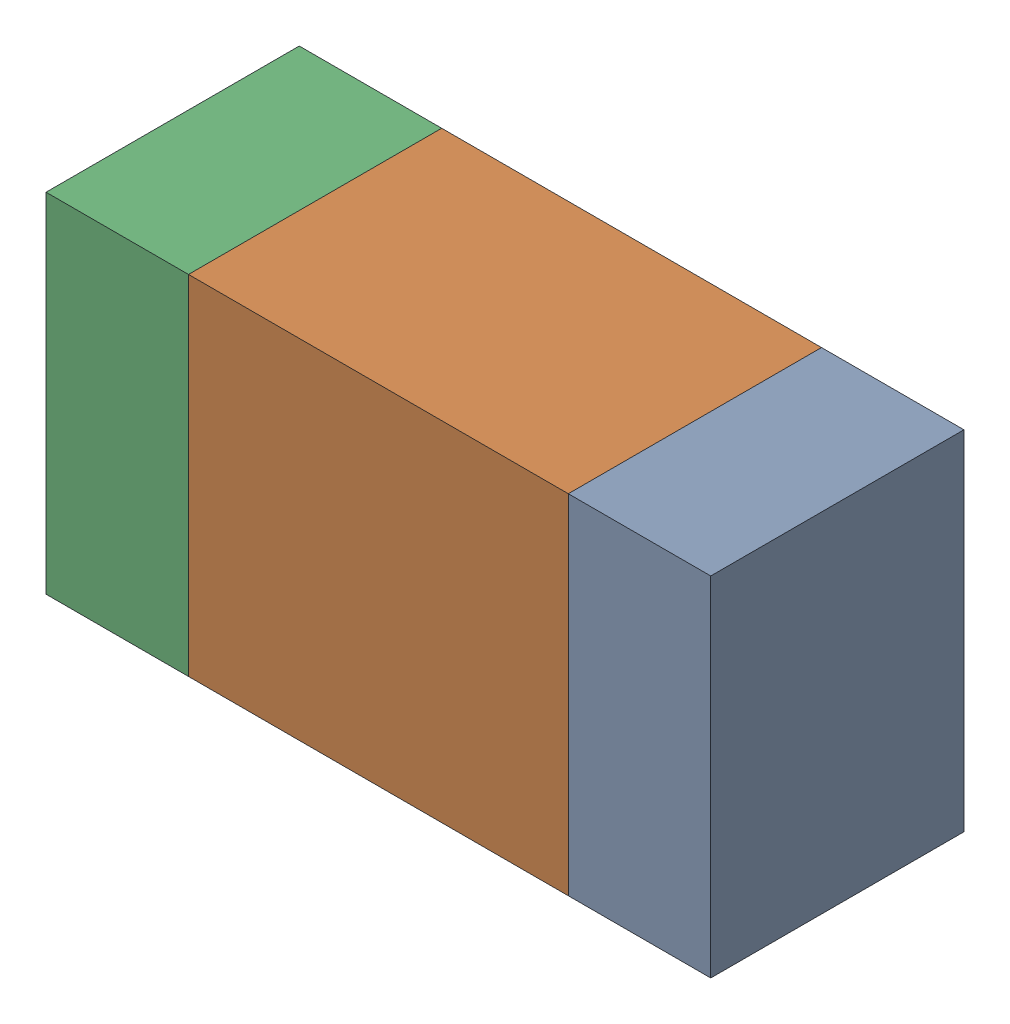
SolidWorks assembly R200PCB, configuration Default. Lengths in mm.
Overall size (1.05 0.55 0.4).
6 component instances, 2 part files, 0 mates.
Components (placement in the parent):
- 854785432-1: 854785432 [Default] at (122.0124 123.6001 -2.0638) size (0.22 0.55 0.4)
  - Extruded-1: Extruded [Default] at origin size (0.22 0.55 0.4)
- 854785568-1: 854785568 [Default] at (121.5999 123.6001 -2.0638) size (0.6 0.55 0.4)
  - Extruded_2-1: Extruded_2 [Default] at origin size (0.6 0.55 0.4)
- 854785432-2: 854785432 [Default] at (121.1874 123.6001 -2.0638) size (0.22 0.55 0.4)
  - Extruded-1: Extruded [Default] at origin size (0.22 0.55 0.4)
